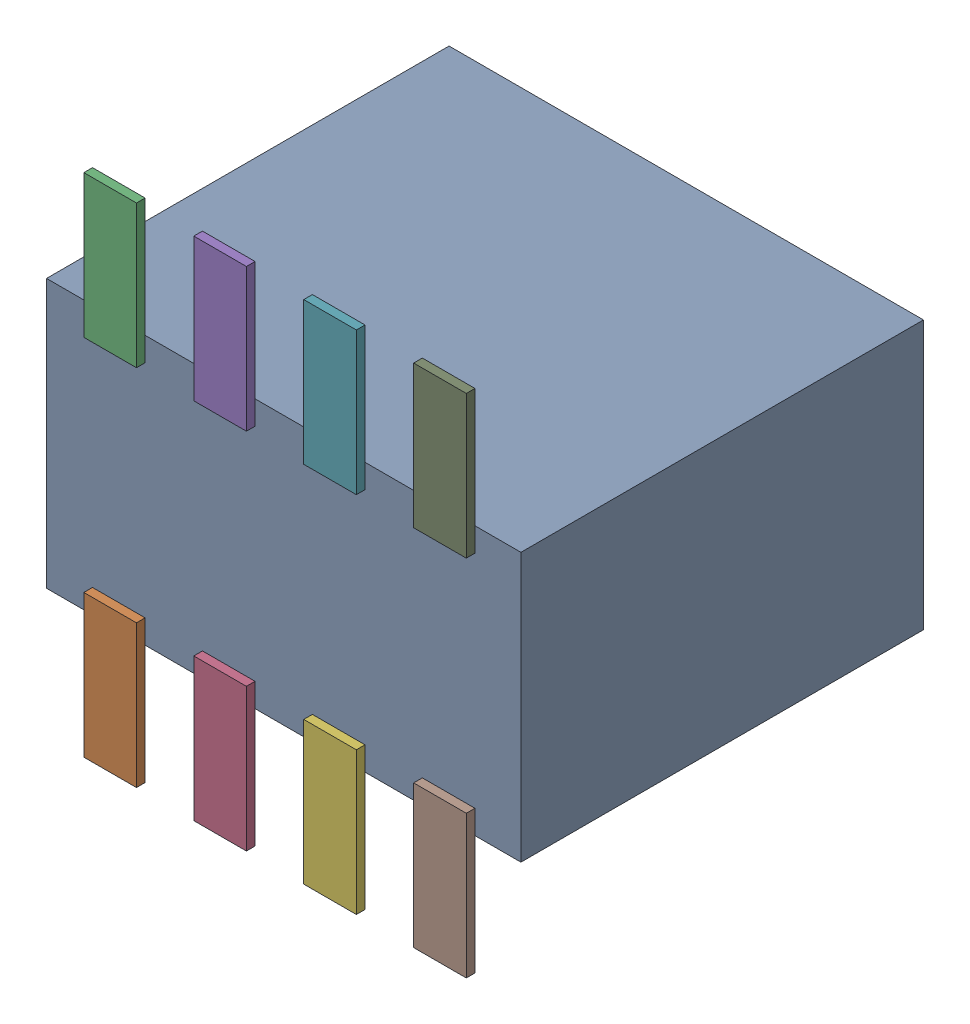
SolidWorks assembly J2, configuration Default. Lengths in mm.
Overall size (5.48 5.85 4.75).
3 component instances, 2 part files, 0 mates.
Components (placement in the parent):
- 9705581488-1: 9705581488 [Default] at (208.451 98.62 -1.0914) x (1 0 0) z (0 0 -1) size (5.48 5.85 4.75)
  - Body-1: Body [Default] at (0 0 0.1) size (5.48 3.1 4.65)
  - Pins-1: Pins [Default] at origin size (4.42 5.85 0.1)
